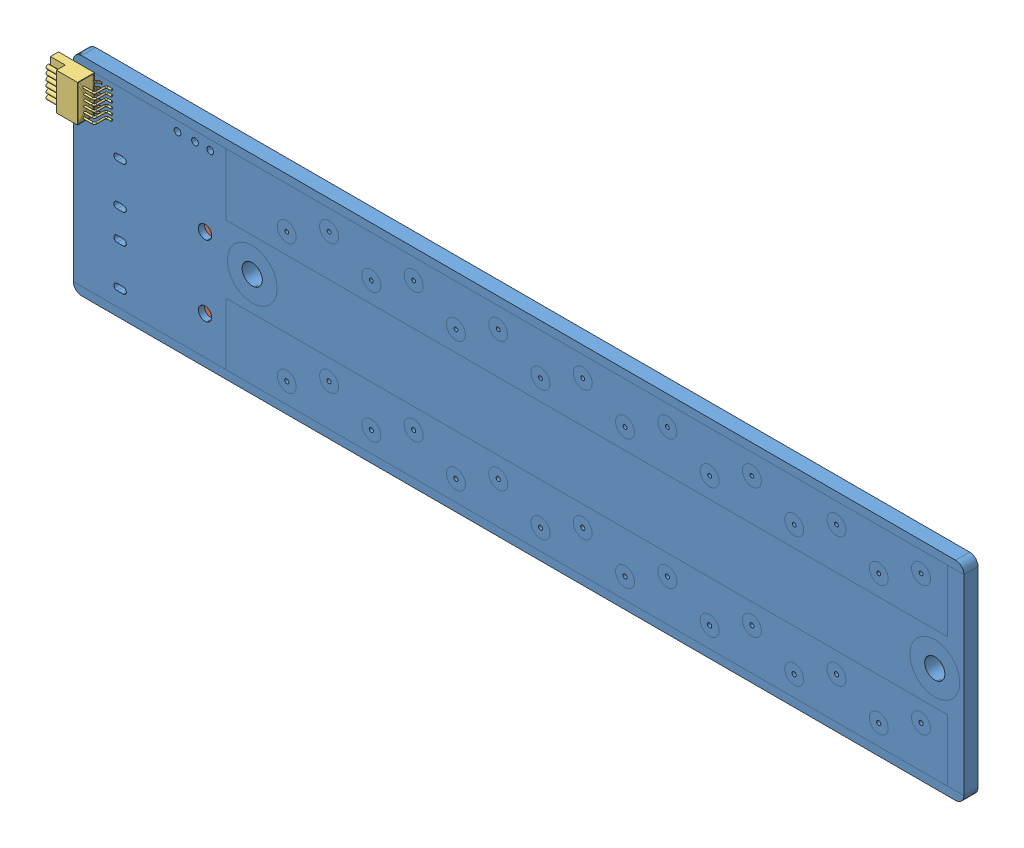
SolidWorks assembly two connector board asm, configuration Default. Lengths in mm.
Overall size (108.78 25 10.13).
4 component instances, 3 part files, 10 mates.
Components (placement in the parent):
- board-1: board [Default] at origin size (107 25 1.69)
- Jack PCB-1: Jack PCB [Default] at (-45.55 -6.925 -3.2) x (-1 0 0) z (0 -1 0) size (19.05 7.4 7.9)
- Jack PCB-2: Jack PCB [Default] at (-45.55 1.575 -3.2) x (-1 0 0) z (0 -1 0) size (19.05 7.4 7.9)
- A79623-001-1: A79623-001 [Default] at (-50.96 9.2775 1.692) x (0 -1 0) z (-1 0 0) size (4.45 2.05 6.53)
Mates (geometry in assembly coordinates):
- Coincident1: coordinate: point of board-1; point of assembly
- Concentric1: concentric aligned: cylinder of Jack PCB-1 through (-37.675 -6.925 1) axis (0 0 -1) radius 0.75; cylinder of board-1 through (-37.675 -6.925 10) axis (0 0 -1) radius 0.8
- Coincident2: coincident anti-aligned: plane of board-1 through (0 0 0) normal (0 0 -1); plane of Jack PCB-1 through (-36.025 -10.875 0) normal (0 0 1)
- Concentric4: concentric aligned: cylinder of board-1 through (-37.675 1.575 10) axis (0 0 -1) radius 0.8; cylinder of Jack PCB-2 through (-37.675 1.575 1) axis (0 0 -1) radius 0.75
- Coincident3: coincident anti-aligned: plane of board-1 through (0 0 0) normal (0 0 -1); plane of Jack PCB-2 through (-36.025 -2.375 0) normal (0 0 1)
- Coincident4: coincident aligned: plane of board-1 through (-53.5 0 1.692) normal (-1 0 0); plane of A79623-001-1 through (-53.5 7.055 2.6572) normal (-1 0 0)
- Coincident5: coincident anti-aligned: plane of board-1 through (0 0 1.692) normal (0 0 1); plane of A79623-001-1 through (-50.96 7.055 1.692) normal (0 0 -1)
- Coincident6: coincident aligned: line of board-1 through (-35.15 11.5 1.692) axis (-1 0 0); line of A79623-001-1 through (-50.96 11.5 1.692) axis (-1 0 0)
- Parallel1: parallel anti-aligned: plane of Jack PCB-1 through (-45.55 -2.975 -3.2) normal (0 1 0); plane of Jack PCB-2 through (-45.55 -2.375 -3.2) normal (0 -1 0)
- Parallel2: parallel: line of board-1 through (105 -52.5 12.5) axis (0 1 0); plane of Jack PCB-2 through (-45.55 5.525 -3.2) normal (0 1 0)
